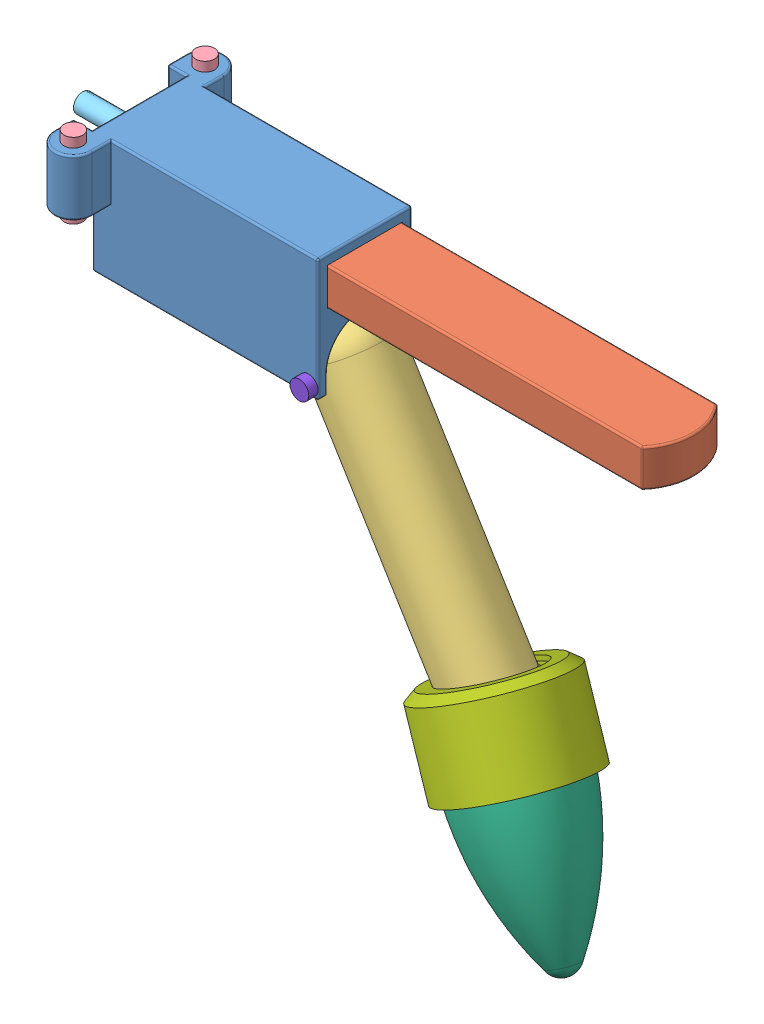
SolidWorks assembly Sistema de brazo, configuration Predeterminado. Lengths in mm.
Overall size (325 296.12 97.34).
9 component instances, 8 part files, 17 mates.
Components (placement in the parent):
- Brazo1-1: Brazo1 [Predeterminado] at (-6.6953 0.9378 140) size (130 65 90)
- Brazo2-1: Brazo2 [Predeterminado] at (138.3047 5.9378 140) size (180 20 40)
- Pierna1-1: Pierna1 [Predeterminado] at (62.9132 -52.8546 139.8431) x (0.523238 -0.852186 0) z (0 0 1) size (200 50 50)
- UnionB1Cuerpo-1: UnionB1Cuerpo [Predeterminado] at (-66.6953 15.9378 105) x (0 1 0) z (0 0 1) size (40 10 10)
- UnionB1Cuerpo-2: UnionB1Cuerpo [Predeterminado] at (-66.6953 15.9378 175) x (0 1 0) z (-0.093327 0 0.995636) size (40 10 10)
- TornilloSinFin-1: TornilloSinFin [Predeterminado] at (3.3047 15.3473 142.4293) x (-1 0 0) z (0 0.236172 -0.971711) size (200.01 11.57 10.02)
- Pierna2-1: Pierna2 [Predeterminado] at (147.9923 -196.0918 146.0658) x (0.47115 -0.871146 0.138281) z (-0.852159 -0.490023 -0.183583) size (101.24 60 60)
- UnionPierna-1: UnionPierna [Predeterminado] at (131.0308 -164.7305 141.0877) x (0.779844 0.484657 0.396172) z (-0.412142 -0.078819 0.907704) size (70 43.91 70)
- UnionB1P1-1: UnionB1P1 [Predeterminado] at (48.3047 -29.0622 139.8431) x (0 0 -1) z (-0.115361 0.993324 0) size (60 10 10)
Mates (geometry in assembly coordinates):
- Coincidente1: coincident anti-aligned: plane of Brazo1-1 through (-101.4166 25.9378 160) normal (0 0 -1); plane of Brazo2-1 through (48.3047 25.9378 160) normal (0 0 1)
- Coincidente2: coincident anti-aligned: plane of Brazo1-1 through (-101.4166 25.9378 160) normal (0 -1 0); plane of Brazo2-1 through (198.3047 25.9378 140) normal (0 1 0)
- Concéntrica20: concentric anti-aligned: cylinder of Brazo1-1 through (-66.6953 0.9368 105) axis (0 1 0) radius 5; cylinder of UnionB1Cuerpo-1 through (-66.6953 -23.5642 105) axis (0 -1 0) radius 2.5
- Coincidente7: coincident anti-aligned: plane of Brazo1-1 through (-6.6953 30.9378 140) normal (0 1 0); plane of UnionB1Cuerpo-1 through (-66.6953 30.9378 102.5) normal (0 -1 0)
- Concéntrica21: concentric anti-aligned: circle of Brazo1-1; cylinder of UnionB1Cuerpo-2 through (-66.6953 -23.5642 175) axis (0 -1 0) radius 2.5
- Coincidente8: coincident anti-aligned: plane of Brazo1-1 through (-6.6953 30.9378 140) normal (0 1 0); plane of UnionB1Cuerpo-2 through (-66.4619 30.9378 172.5109) normal (0 -1 0)
- Concéntrica22: concentric anti-aligned: circle of Brazo2-1; circle of TornilloSinFin-1
- Coincidente12: coincident aligned: plane of Brazo1-1 through (-66.6953 30.9378 165) normal (-1 0 0); plane of TornilloSinFin-1 through (-66.6953 15.3473 142.4293) normal (-1 0 0)
- Distancia límite1: limit distance = 115 mm aligned: plane of Brazo1-1 through (-66.6953 30.9378 165) normal (-1 0 0); plane of Brazo2-1 through (48.3047 25.9378 120) normal (-1 0 0)
- Concéntrica23: concentric anti-aligned: cylinder of Brazo1-1 through (48.3047 -29.0622 172.0711) axis (0 0 -1) radius 2.5; cylinder of Pierna1-1 through (48.3047 -29.0622 114.8431) axis (0 0 1) radius 2.5
- Tangente1: tangent: curve of Brazo1-1; curve of Pierna1-1
- Concéntrica24: concentric anti-aligned: cylinder of Brazo1-1 through (48.3047 -29.0622 172.0711) axis (0 0 -1) radius 2.5; cylinder of UnionB1P1-1 through (48.3047 -29.0622 179.3452) axis (0 0 1) radius 2.5
- Bloquear1: lock: unknown of Pierna1-1; unknown of UnionB1P1-1
- Tangente6: tangent aligned: sphere of Pierna1-1; sphere of Pierna2-1
- Concéntrica31: concentric aligned: circle of Pierna2-1; circle of UnionPierna-1
- Ángulo límite1: limit planar angle = 2.121443 rad aligned: cylinder of Pierna1-1 through (29.9045 0.9058 139.8431) axis (-0.523238 0.852186 0) radius 20; cylinder of Brazo1-1 through (-66.6953 -24.0622 140) axis (1 0 0) radius 20
- Coincidente19: coincident anti-aligned: circle of Pierna2-1; plane of UnionPierna-1 through (161.9645 -164.1291 155.1853) normal (0.47115 -0.871146 0.138281)
